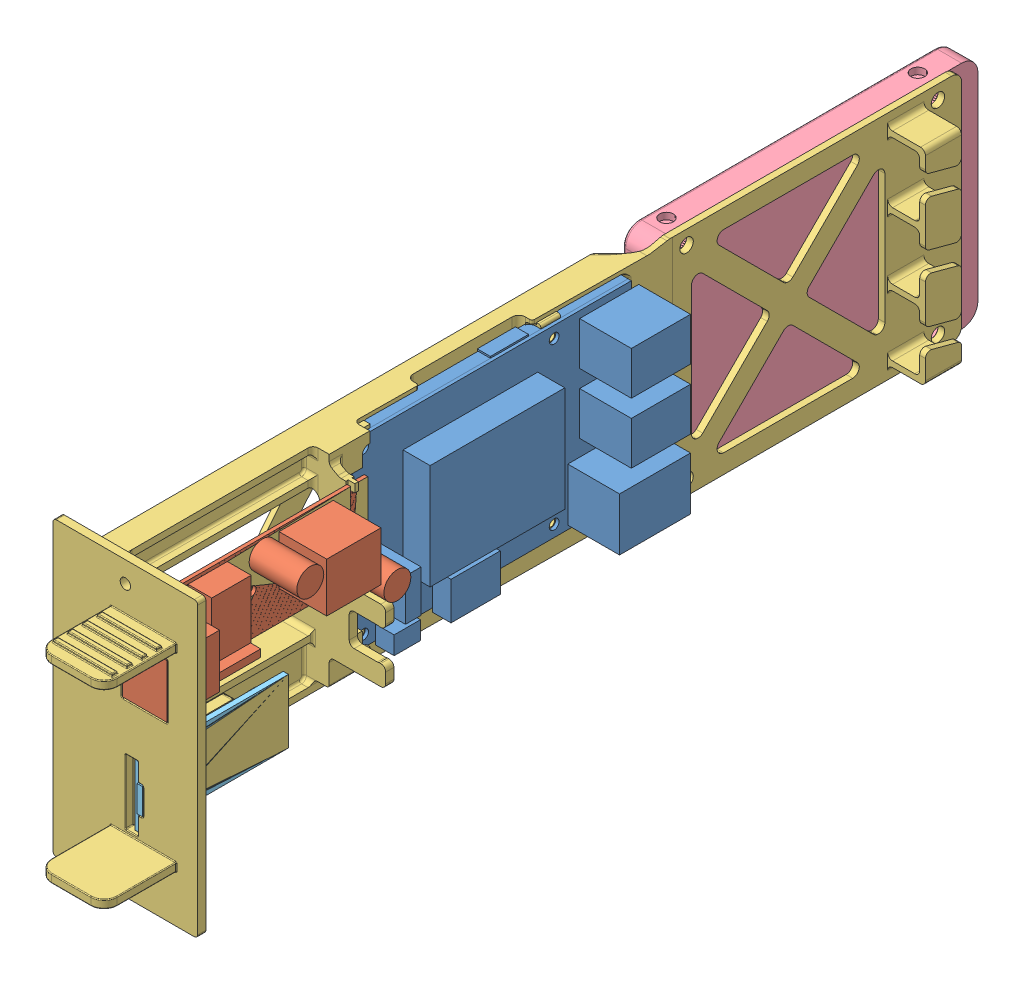
SolidWorks assembly Assem1, configuration Default. Lengths in mm.
Overall size (44 88.9 294.5).
5 component instances, 5 part files, 15 mates.
Components (placement in the parent):
- ODroid_C2.2-1: ODroid_C2.2 [Default] at (-10 4 -120.5) x (0 0 1) z (1 0 0) size (87.25 57.65 20.75)
- POE-1: POE [Default] at (-2 16 -39.305) x (0 0 -1) z (1 0 0) size (74.68 25.1 17.85)
- Rack_base-2: Rack_base [Default] x (-1 0 0) z (0 0 -1) size (44 88.9 287.5)
- SSD-1: SSD [Default] at (-13 0 -172.5) x (0 0 -1) z (-1 0 0) size (100 70.15 8.25)
- UART-FT232-1: UART-FT232 [Default] at (2 -7 -1) x (0 1 0) z (0 0 -1) size (19.4 4.8 46.1)
Mates (geometry in assembly coordinates):
- Coincident12: coincident anti-aligned: plane of Rack_base-2 through (0 0 0) normal (-1 0 0); plane of assembly through (0 0 0) normal (1 0 0)
- Distance7: distance = 0 mm aligned: plane of Rack_base-2; plane of assembly through (0 0 0) normal (0 1 0)
- Coincident3: coincident anti-aligned: plane of Rack_base-2 through (0 0 0) normal (0 0 -1); plane of assembly through (0 0 0) normal (0 0 1)
- Distance1: distance = 78 mm anti-aligned: plane of Rack_base-2 through (0 0 0) normal (0 0 -1); plane of ODroid_C2.2-1 through (-13.75 -23.975 -78) normal (0 0 1)
- Distance6: distance = 10 mm anti-aligned: plane of ODroid_C2.2-1 through (-10 4 -120.5) normal (1 0 0); plane of Rack_base-2 through (0 0 0) normal (-1 0 0)
- Distance16: distance = 4 mm anti-aligned: plane of ODroid_C2.2-1; plane of Rack_base-2
- Distance3: distance = 8 mm aligned: plane of POE-1 through (-2 16 -39.305) normal (1 0 0); plane of ODroid_C2.2-1 through (-10 4 -120.5) normal (1 0 0)
- Coincident17: coincident aligned: plane of POE-1 through (12.6 24.15 0) normal (0 0 1); plane of Rack_base-2 through (0 0 0) normal (0 0 1)
- Distance12: distance = 12 mm anti-aligned: plane of POE-1; plane of ODroid_C2.2-1
- Distance14: distance = 3 mm anti-aligned: plane of ODroid_C2.2-1 through (-10 4 -120.5) normal (1 0 0); plane of SSD-1 through (-13 0 -172.5) normal (-1 0 0)
- Distance13: distance = 52 mm anti-aligned: plane of ODroid_C2.2-1; plane of SSD-1
- Distance17: distance = 0 mm anti-aligned: plane of Rack_base-2; plane of SSD-1
- Distance18: distance = 1 mm aligned: plane of Rack_base-2 through (0 0 0) normal (0 0 -1); plane of UART-FT232-1 through (2 -7 -1) normal (0 0 -1)
- Distance20: distance = 2 mm anti-aligned: plane of Rack_base-2 through (0 0 0) normal (-1 0 0); plane of UART-FT232-1
- Distance19: distance = 7 mm aligned: plane of UART-FT232-1; plane of Rack_base-2
